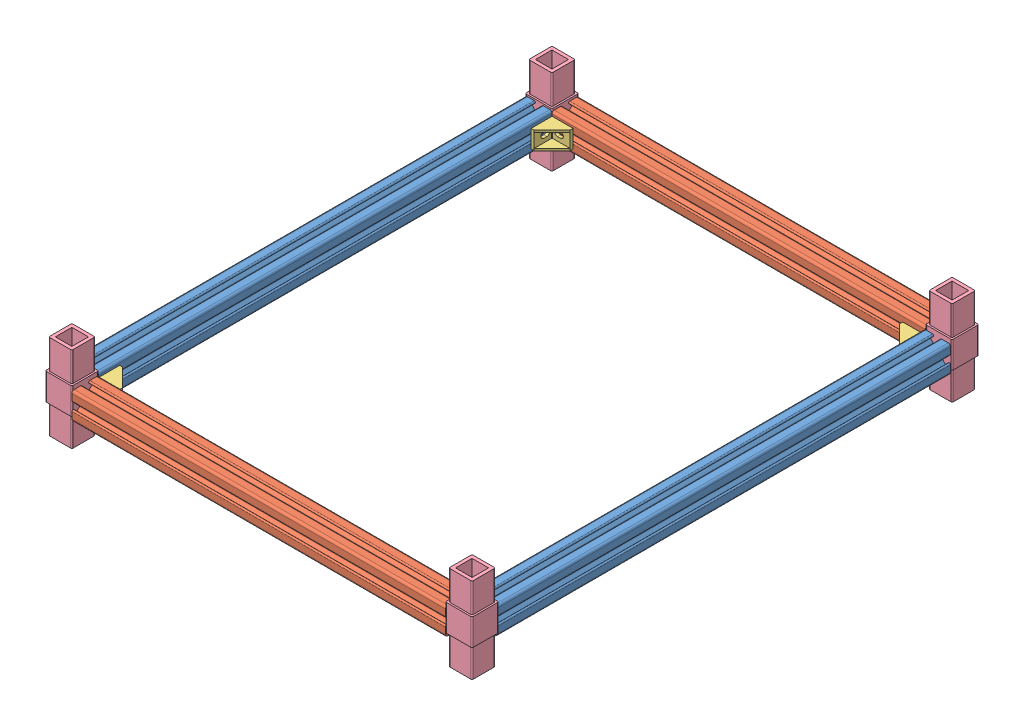
SolidWorks assembly Rack Level V2, configuration Default. Lengths in mm.
Overall size (406.56 81.28 482.6).
12 component instances, 4 part files, 34 mates.
Components (placement in the parent):
- connector_rod_17in-1: connector_rod_17in [Default] at (244.6451 248.7296 254.5249) size (25.4 25.4 431.8)
- connector_rod_17in-2: connector_rod_17in [Default] at (623.9342 246.0174 254.5249) size (25.4 25.4 431.8)
- connector_rod_14in-1: connector_rod_14in [Default] at (435.1457 246.5198 483.1249) x (0 0 -1) z (1 0 0) size (25.4 25.4 355.6)
- connector_rod_14in-2: connector_rod_14in [Default] at (434.9859 248.2272 25.9249) x (0 0 -1) z (1 0 0) size (25.4 25.4 355.6)
- corner_bracket8-1: corner_bracket8 [Default] at (257.3451 248.4784 38.6249) x (0 1 0) z (1 0 0) size (17 21.5 21.5)
- corner_bracket8-3: corner_bracket8 [Default] at (257.3451 248.9808 470.4249) x (0 1 0) z (0 0 -1) size (17 21.5 21.5)
- corner_bracket8-4: corner_bracket8 [Default] at (611.2342 245.7662 38.6249) x (0 1 0) z (0 0 1) size (17 21.5 21.5)
- corner_bracket8-5: corner_bracket8 [Default] at (611.2342 246.2686 470.4249) x (0 -1 0) z (0 0 -1) size (17 21.5 21.5)
- 9215-1: 9215 [Default] at (625.4859 250.333 25.9249) x (0 1 0) z (0 0 1) size (81.28 25.4 25.4)
- 9215-2: 9215 [Default] at (244.4859 250.333 25.9249) x (0 1 0) z (0 0 1) size (81.28 25.4 25.4)
- 9215-3: 9215 [Default] at (244.6457 250.333 483.1249) x (0 1 0) z (0 0 1) size (81.28 25.4 25.4)
- 9215-4: 9215 [Default] at (625.6457 250.333 483.1249) x (0 1 0) z (0 0 1) size (81.28 25.4 25.4)
Mates (geometry in assembly coordinates):
- Coincident1: coincident anti-aligned: plane of connector_rod_17in-1 through (257.3451 253.0857 470.4249) normal (1 0 0); plane of corner_bracket8-1 through (257.3451 256.9784 38.6249) normal (-1 0 0)
- Tangent1: tangent anti-aligned: cylinder of connector_rod_17in-1 through (256.2402 244.3735 470.4249) axis (0 0 -1) radius 1.1049; plane of corner_bracket8-1 through (257.3451 245.4784 38.6249) normal (0 -1 0)
- Coincident2: coincident aligned: plane of connector_rod_17in-1 through (233.05 244.3735 38.6249) normal (0 0 -1); plane of corner_bracket8-1 through (277.3451 256.9784 38.6249) normal (0 0 -1)
- Coincident3: coincident anti-aligned: plane of connector_rod_14in-2 through (612.7859 258.819 38.6249) normal (0 0 1); plane of corner_bracket8-1 through (277.3451 256.9784 38.6249) normal (0 0 -1)
- Tangent2: tangent anti-aligned: cylinder of connector_rod_14in-2 through (612.7859 252.5833 37.52) axis (-1 0 0) radius 1.1049; plane of corner_bracket8-1 through (257.3451 251.4784 38.6249) normal (0 1 0)
- Coincident4: coincident anti-aligned: plane of connector_rod_17in-2 through (611.2342 256.6092 470.4249) normal (-1 0 0); plane of corner_bracket8-4 through (611.2342 254.2662 58.6249) normal (1 0 0)
- Tangent3: tangent anti-aligned: cylinder of connector_rod_17in-2 through (612.3391 241.6613 470.4249) axis (0 0 -1) radius 1.1049; plane of corner_bracket8-4 through (611.2342 242.7662 38.6249) normal (0 -1 0)
- Coincident5: coincident aligned: plane of connector_rod_17in-2 through (612.3391 241.6613 38.6249) normal (0 0 -1); plane of corner_bracket8-4 through (611.2342 254.2662 38.6249) normal (0 0 -1)
- Coincident6: coincident anti-aligned: plane of connector_rod_17in-1 through (257.3451 253.0857 470.4249) normal (1 0 0); plane of corner_bracket8-3 through (257.3451 257.4808 450.4249) normal (-1 0 0)
- Tangent4: tangent anti-aligned: cylinder of connector_rod_17in-1 through (256.2402 253.0857 470.4249) axis (0 0 -1) radius 1.1049; plane of corner_bracket8-3 through (257.3451 251.9808 470.4249) normal (0 1 0)
- Coincident7: coincident aligned: plane of connector_rod_17in-1 through (233.05 244.3735 470.4249) normal (0 0 1); plane of corner_bracket8-3 through (257.3451 257.4808 470.4249) normal (0 0 1)
- Coincident8: coincident anti-aligned: plane of connector_rod_14in-1 through (612.9457 235.928 470.4249) normal (0 0 -1); plane of corner_bracket8-3 through (257.3451 257.4808 470.4249) normal (0 0 1)
- Tangent7: tangent aligned: cylinder of connector_rod_14in-1 through (612.9457 250.8759 471.5298) axis (-1 0 0) radius 1.1049; plane of corner_bracket8-3 through (257.3451 251.9808 470.4249) normal (0 1 0)
- Coincident10: coincident anti-aligned: plane of connector_rod_14in-2 through (612.7859 258.819 38.6249) normal (0 0 1); plane of corner_bracket8-4 through (611.2342 254.2662 38.6249) normal (0 0 -1)
- Tangent8: tangent aligned: cylinder of connector_rod_14in-2 through (612.7859 243.8711 37.52) axis (-1 0 0) radius 1.1049; plane of corner_bracket8-4 through (611.2342 242.7662 38.6249) normal (0 -1 0)
- Tangent9: tangent aligned: cylinder of connector_rod_14in-1 through (612.9457 250.8759 471.5298) axis (-1 0 0) radius 1.1049; plane of corner_bracket8-3 through (257.3451 251.9808 470.4249) normal (0 1 0)
- Coincident11: coincident anti-aligned: plane of connector_rod_17in-2 through (611.2342 256.6092 470.4249) normal (-1 0 0); plane of corner_bracket8-5 through (611.2342 237.7686 450.4249) normal (1 0 0)
- Tangent10: tangent anti-aligned: cylinder of connector_rod_17in-2 through (612.3391 250.3735 470.4249) axis (0 0 -1) radius 1.1049; plane of corner_bracket8-5 through (611.2342 249.2686 470.4249) normal (0 1 0)
- Coincident12: coincident anti-aligned: plane of connector_rod_14in-1 through (612.9457 250.8759 470.4249) normal (0 0 -1); plane of corner_bracket8-5 through (611.2342 237.7686 470.4249) normal (0 0 1)
- Tangent11: tangent anti-aligned: cylinder of connector_rod_17in-2 through (612.3391 250.3735 470.4249) axis (0 0 -1) radius 1.1049; plane of corner_bracket8-5 through (611.2342 249.2686 470.4249) normal (0 1 0)
- Tangent12: tangent anti-aligned: cylinder of connector_rod_14in-1 through (612.9457 242.1637 471.5298) axis (-1 0 0) radius 1.1049; plane of corner_bracket8-5 through (611.2342 243.2686 470.4249) normal (0 -1 0)
- Coincident21: coincident anti-aligned: plane of connector_rod_14in-2 through (612.7859 243.8711 37.52) normal (1 0 0); plane of 9215-1 through (612.7859 253.3107 14.4949) normal (-1 0 0)
- Coincident22: coincident anti-aligned: plane of connector_rod_17in-2 through (612.3391 241.6613 38.6249) normal (0 0 -1); plane of 9215-1 through (614.0559 253.3107 38.6249) normal (0 0 1)
- Coincident23: coincident anti-aligned: plane of connector_rod_17in-1 through (233.05 244.3735 38.6249) normal (0 0 -1); plane of 9215-2 through (233.0559 263.033 38.6249) normal (0 0 1)
- Coincident24: coincident anti-aligned: plane of connector_rod_14in-2 through (257.1859 243.8711 37.52) normal (-1 0 0); plane of 9215-2 through (257.1859 263.033 37.3549) normal (1 0 0)
- Coincident25: coincident anti-aligned: plane of connector_rod_14in-1 through (612.9457 242.1637 494.72) normal (1 0 0); plane of 9215-4 through (612.9457 253.3107 471.6949) normal (-1 0 0)
- Coincident26: coincident anti-aligned: plane of connector_rod_17in-2 through (612.3391 241.6613 470.4249) normal (0 0 1); plane of 9215-4 through (637.0757 253.3107 470.4249) normal (0 0 -1)
- Coincident27: coincident anti-aligned: plane of connector_rod_14in-1 through (257.3457 242.1637 494.72) normal (-1 0 0); plane of 9215-3 through (257.3457 263.033 494.5549) normal (1 0 0)
- Coincident28: coincident anti-aligned: plane of connector_rod_17in-1 through (233.05 244.3735 470.4249) normal (0 0 1); plane of 9215-3 through (256.0757 263.033 470.4249) normal (0 0 -1)
- Parallel1: parallel aligned: plane of 9215-3 through (254.4247 209.693 492.9039) normal (0 -1 0); plane of 9215-4 through (635.4247 199.9707 492.9039) normal (0 -1 0)
- Parallel2: parallel aligned: plane of 9215-1 through (635.2649 199.9707 35.7039) normal (0 -1 0); plane of 9215-2 through (254.2649 209.693 35.7039) normal (0 -1 0)
- Coincident31: coincident aligned: plane of 9215-2 through (254.2649 209.693 35.7039) normal (0 -1 0); plane of 9215-3 through (254.4247 209.693 492.9039) normal (0 -1 0)
- Coincident32: coincident aligned: plane of 9215-1 through (635.2649 209.693 35.7039) normal (0 -1 0); plane of 9215-4 through (635.4247 209.693 492.9039) normal (0 -1 0)
- Coincident33: coincident aligned: plane of 9215-1 through (635.2649 209.693 35.7039) normal (0 -1 0); plane of 9215-2 through (254.2649 209.693 35.7039) normal (0 -1 0)
